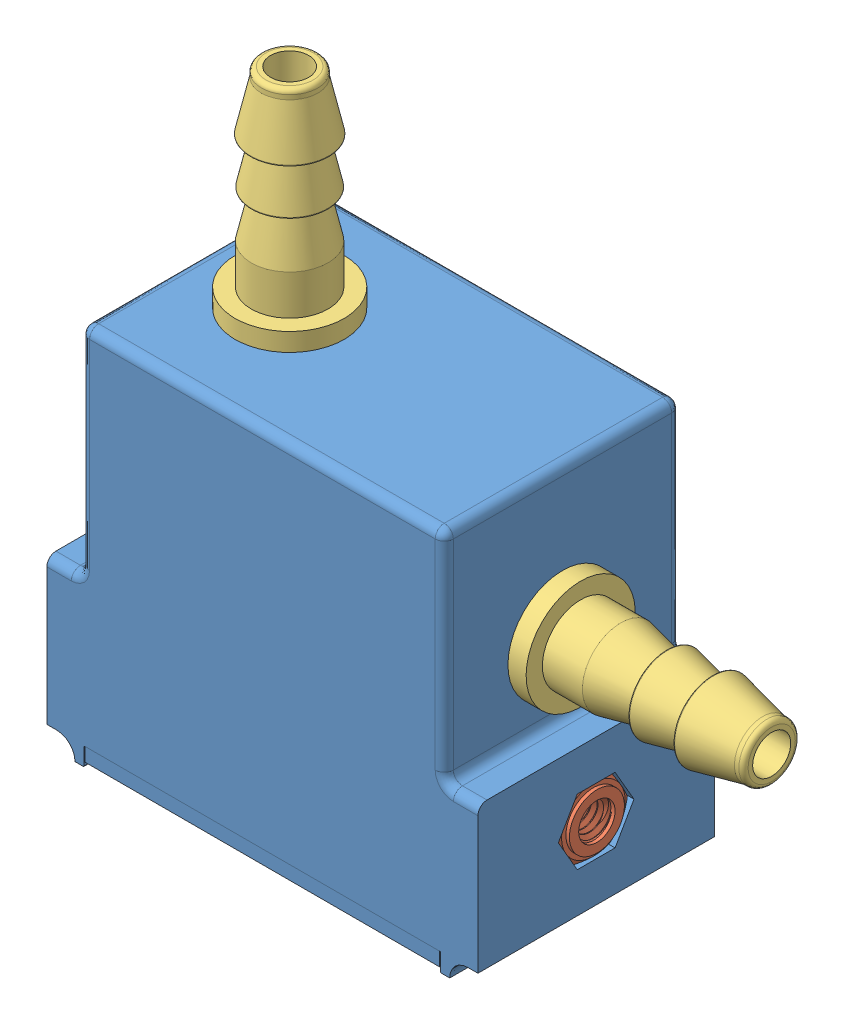
SolidWorks assembly Thermal_Block_Assembly_P, configuration Default. Lengths in mm.
Overall size (66.78 65 26).
5 component instances, 3 part files, 8 mates.
Components (placement in the parent):
- Thermal_Block_P-1: Thermal_Block_P [Default] at (18.4797 6.8646 35.2017) size (47.4 42 26)
- M4 x 0.7 Hex Nut-1: M4 x 0.7 Hex Nut [90592A090] at (40.2797 14.8646 35.2017) x (0 -1 0) z (0 0 1) size (7 3.86 8.08)
- M4 x 0.7 Hex Nut-2: M4 x 0.7 Hex Nut [90592A090] at (-3.3203 14.8646 35.2017) x (0 1 0) z (0 0 1) size (7 3.86 8.08)
- Tube_Fitting_Final-1: Tube_Fitting_Final [Default] at (40.4797 30.8646 35.2017) x (1 0 0) z (0 0.787568 -0.616227) size (23 12 12)
- Tube_Fitting_Final-2: Tube_Fitting_Final [Default] at (8.4797 48.8646 35.2017) x (0 1 0) z (0 0 1) size (23 12 12)
Mates (geometry in assembly coordinates):
- Coincident1: coincident anti-aligned: plane of Thermal_Block_P-1 through (38.6797 6.8646 35.2017) normal (1 0 0); plane of M4 x 0.7 Hex Nut-1 through (38.6797 18.3646 33.181) normal (-1 0 0)
- Concentric1: concentric aligned: circle of Thermal_Block_P-1; circle of M4 x 0.7 Hex Nut-1
- Coincident2: coincident anti-aligned: plane of Thermal_Block_P-1 through (-1.7203 6.8646 35.2017) normal (-1 0 0); plane of M4 x 0.7 Hex Nut-2 through (-1.7203 11.3646 33.181) normal (1 0 0)
- Concentric2: concentric anti-aligned: circle of Thermal_Block_P-1; circle of M4 x 0.7 Hex Nut-2
- Parallel1: parallel anti-aligned: plane of Thermal_Block_P-1 through (38.6797 14.8646 39.3586) normal (0 -0.5 -0.866025); plane of M4 x 0.7 Hex Nut-1 through (41.8797 18.3646 37.2224) normal (0 0.5 0.866025)
- Parallel2: parallel anti-aligned: plane of Thermal_Block_P-1 through (-1.7203 18.4646 37.2801) normal (0 -1 0); plane of M4 x 0.7 Hex Nut-2 through (-4.9203 18.3646 37.2224) normal (0 1 0)
- Coincident5: coincident anti-aligned: circle of Thermal_Block_P-1; circle of Tube_Fitting_Final-1
- Coincident6: coincident anti-aligned: circle of Thermal_Block_P-1; circle of Tube_Fitting_Final-2
